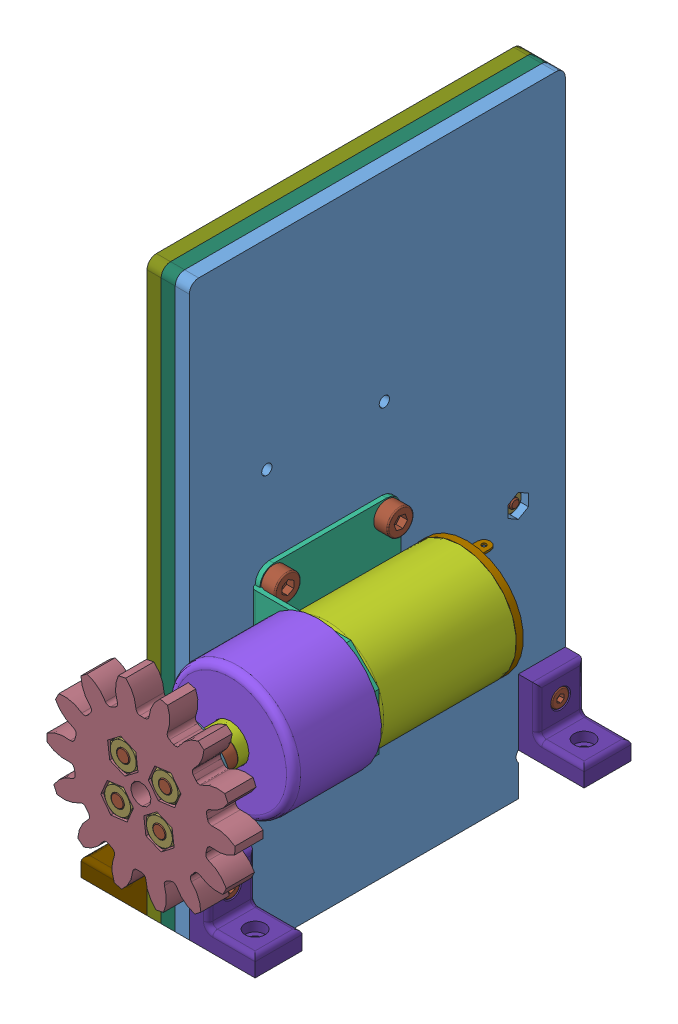
SolidWorks assembly moteur-complet, configuration Défaut. Lengths in mm.
Overall size (65.16 130 104.7).
48 component instances, 19 part files, 74 mates.
Components (placement in the parent):
- moteur-platine-1-4: moteur-platine-1 [Défaut] at (-59.9962 -68.9698 170) size (3 130 80)
- Grove button-1: Grove button [Défaut] at (-66.7015 -12.8903 110) x (0 -1 0) z (0 0 -1) size (20 11.6 23.6)
  - PCB grove 20x20-1: PCB grove 20x20 [Défaut] at (2.0795 1.2947 0) size (20 1.6 23.6)
  - 603 resistor 102-1: 603 resistor 102 [Default] at (2.0895 2.8947 -6.319) x (0 0 1) z (-1 0 0) size (2.36 0.62 1.03)
  - tactileswitch-CMS-1: tactileswitch-CMS [Default] at (-2.4169 2.8947 0.0035) x (0 0 1) z (-1 0 0) size (8.41 4.95 6.01)
  - Connecteur Grove (droit CMS)-1: Connecteur Grove (droit CMS) [Défaut] at (5.0795 2.8947 0) x (-1 0 0) z (0 1 0) size (6.5 14 10)
  - 603 resistor 102-2: 603 resistor 102 [Default] at (3.5895 2.8947 -6.319) x (0 0 1) z (-1 0 0) size (2.36 0.62 1.03)
- moteur MFA-1: moteur MFA [Défaut] at (-44.4916 -13.5198 141.6132) x (0 0 -1) z (0 -1 0) size (69.13 27.9 30)
  - moteur-support-1: moteur-support [Défaut] at (-14.3868 -12.5047 0) size (31 26.4 30)
  - moteur-corps-1: moteur-corps [Défaut] at (14.8132 1.8953 0) x (0 0 1) z (-1 0 0) size (24 24 62.63)
  - moteur-capuchon-1: moteur-capuchon [Défaut] at (-15.3868 1.8953 0) x (0 0 1) z (-1 0 0) size (27 27 18.7)
  - moteur-arriere-1: moteur-arriere [Défaut] at (16.3132 1.8953 0) x (0 0 1) z (-1 0 0) size (24 24 6.5)
- entretoise-grove-6: entretoise-grove [Défaut] at (-67.9962 -14.9698 120) x (0 0.014606 -0.999893) z (1 0 0) size (4 4 2)
- entretoise-grove-7: entretoise-grove [Défaut] at (-67.9962 -14.9698 100) x (0 0.432952 0.901417) z (1 0 0) size (4 4 2)
- vis-chc-1: vis-chc [Vis CHC M2x12] at (-69.5962 -14.9698 100) x (0 0.697993 -0.716105) z (0 0.716105 0.697993) size (3.8 14 3.8)
- vis-chc-2: vis-chc [Vis CHC M2x12] at (-69.5962 -14.9698 120) x (0 0.185382 -0.982666) z (0 0.982666 0.185382) size (3.8 14 3.8)
- ecrou-h-2: ecrou-h [6007 HU M2] at (-59.9962 -14.9698 120) x (0 0.866025 0.5) z (0 -0.5 0.866025) size (4 1.6 4.62)
- ecrou-h-3: ecrou-h [6007 HU M2] at (-59.9962 -14.9698 100) x (0 0 1) z (0 -1 0) size (4 1.6 4.62)
- vis-chc-8: vis-chc [Vis CHC M3x10] at (-55.9962 -1.5198 129) x (0 0.773717 -0.633531) z (0 -0.633531 -0.773717) size (5.5 13 5.5)
- vis-chc-9: vis-chc [Vis CHC M3x10] at (-55.9962 -1.5198 153) x (0 0.483049 -0.875594) z (0 -0.875594 -0.483049) size (5.5 13 5.5)
- vis-chc-10: vis-chc [Vis CHC M3x10] at (-55.9962 -25.5198 153) x (0 0.381849 -0.924225) z (0 -0.924225 -0.381849) size (5.5 13 5.5)
- vis-chc-11: vis-chc [Vis CHC M3x10] at (-55.9962 -25.5198 129) x (0 0.381849 -0.924225) z (0 -0.924225 -0.381849) size (5.5 13 5.5)
- ecrou-h-9: ecrou-h [6012 HU M3] at (-65.3962 -1.5198 153) x (0 0.866025 0.5) z (0 -0.5 0.866025) size (5.5 2.4 6.35)
- ecrou-h-10: ecrou-h [6012 HU M3] at (-65.3962 -25.5198 153) x (0 0.866025 0.5) z (0 -0.5 0.866025) size (5.5 2.4 6.35)
- ecrou-h-11: ecrou-h [6012 HU M3] at (-65.3962 -25.5198 129) x (0 0.866025 -0.5) z (0 0.5 0.866025) size (5.5 2.4 6.35)
- ecrou-h-12: ecrou-h [6012 HU M3] at (-65.3962 -1.5198 129) x (0 0.866025 -0.5) z (0 0.5 0.866025) size (5.5 2.4 6.35)
- vis-chc-14: vis-chc [Vis CHC M2x16] at (-54.9962 -50.9698 95) x (0 -0.431797 -0.901971) z (0 -0.901971 0.431797) size (3.8 18 3.8)
- vis-chc-15: vis-chc [Vis CHC M2x16] at (-54.9962 -50.9698 165) x (0 0.381849 -0.924225) z (0 -0.924225 -0.381849) size (3.8 18 3.8)
- ecrou-h-15: ecrou-h [6007 HU M2] at (-69.5962 -50.9698 165) x (0 1 0) z (0 0 1) size (4 1.6 4.62)
- ecrou-h-16: ecrou-h [6007 HU M2] at (-69.5962 -50.9698 95) x (0 0.5 0.866025) z (0 -0.866025 0.5) size (4 1.6 4.62)
- engrenage-complet-1: engrenage-complet [Défaut] at (-43.0713 -13.4207 194.7) x (-0.795458 -0.606009 0) z (0 0 -1) size (39.32 40 13)
  - engrenage-1: engrenage [Défaut] at (1.0609 0.1936 0) size (39.32 40 6)
  - vis-chc-2: vis-chc [Vis CHC M3x10] at (6.0322 -0.3667 10) x (0.997256 0.074024 0) z (0.074024 -0.997256 0) size (5.5 13 5.5)
  - ecrou-h-1: ecrou-h [6012 HU M3] at (6.0322 -0.3667 0.1) x (1 0 0) z (0 1 0) size (5.5 2.4 6.35)
  - engrenage-moyeu-1: engrenage-moyeu [Défaut] at (-0.3178 -0.3667 7.5) x (0.707107 -0.707107 0) z (0 0 1) size (19 19 5)
  - vis-chc-3: vis-chc [Vis CHC M3x10] at (-0.3178 5.9833 10) x (0.997256 0.074024 0) z (0.074024 -0.997256 0) size (5.5 13 5.5)
  - vis-chc-4: vis-chc [Vis CHC M3x10] at (-6.6678 -0.3667 10) x (0.997256 0.074024 0) z (0.074024 -0.997256 0) size (5.5 13 5.5)
  - vis-chc-5: vis-chc [Vis CHC M3x10] at (-0.3178 -6.7167 10) x (0.997256 0.074024 0) z (0.074024 -0.997256 0) size (5.5 13 5.5)
  - ecrou-h-2: ecrou-h [6012 HU M3] at (-6.6678 -0.3667 0.1) x (0.5 0.866025 0) z (-0.866025 0.5 0) size (5.5 2.4 6.35)
  - ecrou-h-3: ecrou-h [6012 HU M3] at (-0.3178 5.9833 0.1) x (0.866025 0.5 0) z (-0.5 0.866025 0) size (5.5 2.4 6.35)
  - ecrou-h-4: ecrou-h [6012 HU M3] at (-0.3178 -6.7167 0.1) x (0.866025 0.5 0) z (-0.5 0.866025 0) size (5.5 2.4 6.35)
- moteur-platine-2-5: moteur-platine-2 [Défaut] at (-62.9962 -68.9698 170) size (3 130 80)
- moteur-platine-3-3: moteur-platine-3 [Défaut] at (-65.9962 -68.9698 170) size (3 130 80)
- equerre-3: equerre [Défaut] at (-56.9962 -59.9698 165) x (0 0 -1) z (1 0 0) size (10 14 14)
- equerre-2: equerre [Défaut] at (-56.9962 -59.9698 95) x (0 0 -1) z (1 0 0) size (10 14 14)
- equerre-ecrou-1: equerre-ecrou [Défaut] at (-65.9962 -59.9698 95) x (0 0 1) z (-1 0 0) size (10 14 14)
- equerre-ecrou-2: equerre-ecrou [Défaut] at (-65.9962 -59.9698 165) x (0 0 1) z (-1 0 0) size (10 14 14)
- vis-sthc-m3x5-1: vis-sthc-m3x5 [Défaut] at (-41.6585 -6.5829 187.2) x (-0.051839 0.007008 0.998631) z (0.133961 0.990987 0) size (3.08 3.15 5.22)
Mates (geometry in assembly coordinates):
- Coïncidente1: coincident anti-aligned: plane of moteur-platine-1-4 through (-56.9962 -61.1012 161.1314) normal (1 0 0); plane of moteur MFA-1/moteur-support-1 through (-56.9962 -25.5198 153) normal (-1 0 0)
- Coaxiale1: concentric anti-aligned: cylinder of moteur-platine-1-4 through (-59.9962 -1.5198 129) axis (1 0 0) radius 1.6; cylinder of moteur MFA-1/moteur-support-1 through (-30.5962 -1.5198 129) axis (-1 0 0) radius 1.65
- Coaxiale2: concentric anti-aligned: cylinder of moteur-platine-1-4 through (-59.9962 -25.5198 129) axis (1 0 0) radius 1.6; cylinder of moteur MFA-1/moteur-support-1 through (-30.5962 -25.5198 129) axis (-1 0 0) radius 1.65
- Coaxiale9: concentric anti-aligned: cylinder of Grove button-1/PCB grove 20x20-1 through (-69.5962 -14.9698 120) axis (1 0 0) radius 1.1; cylinder of entretoise-grove-6 through (-65.9962 -14.9698 120) axis (-1 0 0) radius 1.2
- Coaxiale10: concentric anti-aligned: cylinder of Grove button-1/PCB grove 20x20-1 through (-69.5962 -14.9698 100) axis (1 0 0) radius 1.1; cylinder of entretoise-grove-7 through (-65.9962 -14.9698 100) axis (-1 0 0) radius 1.2
- Coïncidente11: coincident anti-aligned: plane of Grove button-1/PCB grove 20x20-1 through (-67.9962 -14.9698 110) normal (1 0 0); plane of entretoise-grove-7 through (-67.9962 -14.9698 100) normal (-1 0 0)
- Coaxiale13: concentric anti-aligned: cylinder of moteur MFA-1/moteur-corps-1 through (-42.5962 -13.5198 189.43) axis (0 0 -1) radius 2; cylinder of engrenage-complet-1/engrenage-bague_arret-1 through (-42.5962 -13.5198 179.93) axis (0 0 1) radius 2.05
- Distance1: distance = 0.5 mm anti-aligned: plane of engrenage-complet-1/engrenage-bague_arret-1 through (-42.5962 -13.5198 179.93) normal (0 0 -1); plane of moteur MFA-1/moteur-corps-1 through (-42.5962 -13.5198 179.43) normal (0 0 1)
- Coïncidente12: coincident anti-aligned: plane of moteur-platine-1-4 through (-59.9962 -61.1012 161.1314) normal (-1 0 0); plane of moteur-platine-2-5 through (-59.9962 -61.1012 161.1314) normal (1 0 0)
- Coïncidente13: coincident aligned: plane of moteur-platine-1-4 through (-56.9962 61.0302 170) normal (0 1 0); plane of moteur-platine-2-5 through (-59.9962 61.0302 170) normal (0 1 0)
- Coïncidente14: coincident aligned: plane of moteur-platine-1-4 through (-56.9962 61.0302 90) normal (0 0 -1); plane of moteur-platine-2-5 through (-59.9962 61.0302 90) normal (0 0 -1)
- Coïncidente15: coincident anti-aligned: plane of moteur-platine-2-5 through (-62.9962 -61.1012 161.1314) normal (-1 0 0); plane of moteur-platine-3-3 through (-62.9962 -61.1012 161.1314) normal (1 0 0)
- Coïncidente16: coincident aligned: plane of moteur-platine-2-5 through (-59.9962 61.0302 170) normal (0 1 0); plane of moteur-platine-3-3 through (-62.9962 61.0302 170) normal (0 1 0)
- Coïncidente17: coincident aligned: plane of moteur-platine-1-4 through (-56.9962 61.0302 90) normal (0 0 -1); plane of moteur-platine-3-3 through (-62.9962 61.0302 90) normal (0 0 -1)
- Coïncidente18: coincident anti-aligned: plane of entretoise-grove-7 through (-65.9962 -14.9698 100) normal (1 0 0); plane of moteur-platine-3-3 through (-65.9962 -61.1012 161.1314) normal (-1 0 0)
- Coïncidente19: coincident anti-aligned: plane of entretoise-grove-6 through (-65.9962 -14.9698 120) normal (1 0 0); plane of moteur-platine-3-3 through (-65.9962 -61.1012 161.1314) normal (-1 0 0)
- Coïncidente21: coincident anti-aligned: plane of Grove button-1/PCB grove 20x20-1 through (-69.5962 -14.9698 110) normal (-1 0 0); plane of vis-chc-2 through (-69.5962 -14.9698 120) normal (1 0 0)
- Coaxiale15: concentric aligned: cylinder of vis-chc-2 through (-57.5962 -14.9698 120) axis (-1 0 0) radius 1; cylinder of ecrou-h-2 through (-58.3962 -14.9698 120) axis (-1 0 0) radius 0.7835
- Parallèle4: parallel aligned: plane of moteur-platine-1-4 through (-56.9962 61.0302 90) normal (0 0 -1); plane of ecrou-h-2 through (-58.3962 -13.8151 118) normal (0 0 -1)
- Coïncidente25: coincident anti-aligned: plane of Grove button-1/PCB grove 20x20-1 through (-69.5962 -14.9698 110) normal (-1 0 0); plane of vis-chc-1 through (-69.5962 -14.9698 100) normal (1 0 0)
- Coaxiale17: concentric aligned: cylinder of vis-chc-1 through (-57.5962 -14.9698 100) axis (-1 0 0) radius 1; cylinder of ecrou-h-3 through (-58.3962 -14.9698 100) axis (-1 0 0) radius 0.7835
- Parallèle5: parallel aligned: plane of moteur-platine-1-4 through (-56.9962 61.0302 90) normal (0 0 -1); plane of ecrou-h-3 through (-58.3962 -13.8151 98) normal (0 0 -1)
- Coaxiale28: concentric anti-aligned: cylinder of moteur MFA-1/moteur-support-1 through (-30.5962 -1.5198 153) axis (-1 0 0) radius 1.65; cylinder of vis-chc-9 through (-65.9962 -1.5198 153) axis (1 0 0) radius 1.5
- Coaxiale29: concentric anti-aligned: cylinder of moteur MFA-1/moteur-support-1 through (-30.5962 -1.5198 129) axis (-1 0 0) radius 1.65; cylinder of vis-chc-8 through (-65.9962 -1.5198 129) axis (1 0 0) radius 1.5
- Coaxiale30: concentric anti-aligned: cylinder of moteur MFA-1/moteur-support-1 through (-30.5962 -25.5198 129) axis (-1 0 0) radius 1.65; cylinder of vis-chc-11 through (-65.9962 -25.5198 129) axis (1 0 0) radius 1.5
- Coaxiale31: concentric anti-aligned: cylinder of moteur MFA-1/moteur-support-1 through (-30.5962 -25.5198 153) axis (-1 0 0) radius 1.65; cylinder of vis-chc-10 through (-65.9962 -25.5198 153) axis (1 0 0) radius 1.5
- Coïncidente43: coincident anti-aligned: plane of moteur MFA-1/moteur-support-1 through (-55.9962 -29.752 156) normal (1 0 0); plane of vis-chc-11 through (-55.9962 -25.5198 129) normal (-1 0 0)
- Coïncidente44: coincident aligned: plane of moteur MFA-1/moteur-support-1 through (-55.9962 -29.752 156) normal (1 0 0); circle of vis-chc-10
- Coïncidente45: coincident anti-aligned: plane of moteur MFA-1/moteur-support-1 through (-55.9962 -29.752 156) normal (1 0 0); plane of vis-chc-8 through (-55.9962 -1.5198 129) normal (-1 0 0)
- Coïncidente46: coincident anti-aligned: plane of moteur MFA-1/moteur-support-1 through (-55.9962 -29.752 156) normal (1 0 0); plane of vis-chc-9 through (-55.9962 -1.5198 153) normal (-1 0 0)
- Coaxiale32: concentric anti-aligned: cylinder of vis-chc-8 through (-65.9962 -1.5198 129) axis (1 0 0) radius 1.5; cylinder of ecrou-h-12 through (-62.9962 -1.5198 129) axis (-1 0 0) radius 1.2295
- Coaxiale33: concentric anti-aligned: cylinder of vis-chc-10 through (-65.9962 -25.5198 153) axis (1 0 0) radius 1.5; cylinder of ecrou-h-10 through (-62.9962 -25.5198 153) axis (-1 0 0) radius 1.2295
- Coaxiale34: concentric anti-aligned: cylinder of vis-chc-9 through (-65.9962 -1.5198 153) axis (1 0 0) radius 1.5; cylinder of ecrou-h-9 through (-62.9962 -1.5198 153) axis (-1 0 0) radius 1.2295
- Coaxiale35: concentric anti-aligned: cylinder of vis-chc-11 through (-65.9962 -25.5198 129) axis (1 0 0) radius 1.5; cylinder of ecrou-h-11 through (-62.9962 -25.5198 129) axis (-1 0 0) radius 1.2295
- Parallèle11: parallel aligned: plane of moteur-platine-3-3 through (-62.9962 -59.9698 170) normal (0 0 1); plane of ecrou-h-10 through (-62.9962 -27.1075 155.75) normal (0 0 1)
- Parallèle12: parallel aligned: plane of moteur-platine-3-3 through (-62.9962 -59.9698 170) normal (0 0 1); plane of ecrou-h-11 through (-62.9962 -27.1075 131.75) normal (0 0 1)
- Parallèle13: parallel aligned: plane of moteur-platine-3-3 through (-62.9962 -59.9698 170) normal (0 0 1); plane of ecrou-h-12 through (-62.9962 -3.1075 131.75) normal (0 0 1)
- Parallèle14: parallel aligned: plane of moteur-platine-3-3 through (-62.9962 -59.9698 170) normal (0 0 1); plane of ecrou-h-9 through (-62.9962 -3.1075 155.75) normal (0 0 1)
- Coïncidente62: coincident anti-aligned: plane of moteur-platine-1-4 through (-56.9962 -61.1012 161.1314) normal (1 0 0); plane of equerre-2 through (-56.9962 -59.9698 95) normal (-1 0 0)
- Coaxiale41: concentric aligned: cylinder of moteur-platine-1-4 through (-59.9962 -50.9698 95) axis (1 0 0) radius 1.1; cylinder of equerre-2 through (-56.9962 -50.9698 95) axis (1 0 0) radius 1.1
- Coïncidente63: coincident aligned: plane of moteur-platine-1-4 through (-56.9962 -59.9698 97.7373) normal (0 -1 0); plane of equerre-2 through (-52.9962 -59.9698 100) normal (0 -1 0)
- Coaxiale42: concentric aligned: cylinder of moteur-platine-1-4 through (-59.9962 -50.9698 165) axis (1 0 0) radius 1.1; cylinder of equerre-3 through (-56.9962 -50.9698 165) axis (1 0 0) radius 1.1
- Coïncidente64: coincident aligned: plane of moteur-platine-1-4 through (-56.9962 -59.9698 162.2627) normal (0 -1 0); plane of equerre-3 through (-52.9962 -59.9698 170) normal (0 -1 0)
- Coïncidente65: coincident anti-aligned: plane of moteur-platine-1-4 through (-56.9962 -61.1012 161.1314) normal (1 0 0); plane of equerre-3 through (-56.9962 -59.9698 165) normal (-1 0 0)
- Coaxiale43: concentric aligned: cylinder of vis-chc-15 through (-70.9962 -50.9698 165) axis (1 0 0) radius 1; cylinder of equerre-3 through (-56.9962 -50.9698 165) axis (1 0 0) radius 1.1
- Coïncidente66: coincident anti-aligned: plane of vis-chc-15 through (-54.9962 -50.9698 165) normal (-1 0 0); plane of equerre-3 through (-54.9962 -50.9698 165) normal (1 0 0)
- Coaxiale44: concentric aligned: cylinder of vis-chc-14 through (-70.9962 -50.9698 95) axis (1 0 0) radius 1; cylinder of equerre-2 through (-56.9962 -50.9698 95) axis (1 0 0) radius 1.1
- Coïncidente67: coincident anti-aligned: plane of vis-chc-14 through (-54.9962 -50.9698 95) normal (-1 0 0); plane of equerre-2 through (-54.9962 -50.9698 95) normal (1 0 0)
- Coïncidente68: coincident anti-aligned: plane of moteur-platine-3-3 through (-65.9962 -61.1012 161.1314) normal (-1 0 0); plane of equerre-ecrou-2 through (-65.9962 -59.9698 165) normal (1 0 0)
- Coïncidente69: coincident anti-aligned: plane of moteur-platine-3-3 through (-65.9962 -61.1012 161.1314) normal (-1 0 0); plane of equerre-ecrou-1 through (-65.9962 -59.9698 95) normal (1 0 0)
- Coïncidente70: coincident aligned: plane of moteur-platine-3-3 through (-62.9962 -59.9698 97.7373) normal (0 -1 0); plane of equerre-ecrou-1 through (-69.9962 -59.9698 90) normal (0 -1 0)
- Coïncidente71: coincident aligned: plane of moteur-platine-3-3 through (-62.9962 -59.9698 97.7373) normal (0 -1 0); plane of equerre-ecrou-2 through (-69.9962 -59.9698 160) normal (0 -1 0)
- Coaxiale45: concentric anti-aligned: cylinder of vis-chc-14 through (-70.9962 -50.9698 95) axis (1 0 0) radius 1; cylinder of equerre-ecrou-1 through (-65.9962 -50.9698 95) axis (-1 0 0) radius 1.1
- Coaxiale46: concentric anti-aligned: cylinder of vis-chc-15 through (-70.9962 -50.9698 165) axis (1 0 0) radius 1; cylinder of equerre-ecrou-2 through (-65.9962 -50.9698 165) axis (-1 0 0) radius 1.1
- Coaxiale47: concentric anti-aligned: cylinder of vis-chc-15 through (-70.9962 -50.9698 165) axis (1 0 0) radius 1; cylinder of ecrou-h-15 through (-67.9962 -50.9698 165) axis (-1 0 0) radius 0.7835
- Parallèle18: parallel anti-aligned: plane of ecrou-h-15 through (-67.9962 -48.9698 166.1547) normal (0 1 0); plane of equerre-ecrou-2 through (-67.9962 -48.8047 166.25) normal (0 -1 0)
- Coïncidente73: coincident anti-aligned: plane of ecrou-h-15 through (-67.9962 -48.9698 163.8453) normal (1 0 0); plane of equerre-ecrou-2 through (-67.9962 -59.9698 165) normal (-1 0 0)
- Coaxiale49: concentric anti-aligned: cylinder of vis-chc-14 through (-70.9962 -50.9698 95) axis (1 0 0) radius 1; cylinder of ecrou-h-16 through (-67.9962 -50.9698 95) axis (-1 0 0) radius 0.7835
- Parallèle19: parallel anti-aligned: plane of ecrou-h-16 through (-67.9962 -48.9698 96.1547) normal (0 1 0); plane of equerre-ecrou-1 through (-67.9962 -48.8047 96.25) normal (0 -1 0)
- Coïncidente75: coincident anti-aligned: plane of ecrou-h-16 through (-67.9962 -48.9698 96.1547) normal (1 0 0); plane of equerre-ecrou-1 through (-67.9962 -59.9698 95) normal (-1 0 0)
- Coïncidente81: coincident anti-aligned: plane of ecrou-h-12 through (-62.9962 0.0679 126.25) normal (1 0 0); plane of moteur-platine-2-5 through (-62.9962 -61.1012 161.1314) normal (-1 0 0)
- Coïncidente82: coincident anti-aligned: plane of ecrou-h-11 through (-62.9962 -23.9321 126.25) normal (1 0 0); plane of moteur-platine-2-5 through (-62.9962 -61.1012 161.1314) normal (-1 0 0)
- Coïncidente83: coincident anti-aligned: plane of ecrou-h-10 through (-62.9962 -22.3444 153) normal (1 0 0); plane of moteur-platine-2-5 through (-62.9962 -61.1012 161.1314) normal (-1 0 0)
- Coïncidente84: coincident anti-aligned: plane of ecrou-h-9 through (-62.9962 1.6556 153) normal (1 0 0); plane of moteur-platine-2-5 through (-62.9962 -61.1012 161.1314) normal (-1 0 0)
- Coaxiale50: concentric anti-aligned: cylinder of vis-chc-2 through (-57.5962 -14.9698 120) axis (-1 0 0) radius 1; cylinder of moteur-platine-3-3 through (-65.9962 -14.9698 120) axis (1 0 0) radius 1
- Coaxiale51: concentric anti-aligned: cylinder of vis-chc-1 through (-57.5962 -14.9698 100) axis (-1 0 0) radius 1; cylinder of moteur-platine-3-3 through (-65.9962 -14.9698 100) axis (1 0 0) radius 1
- Coïncidente85: coincident anti-aligned: plane of ecrou-h-3 through (-59.9962 -13.8151 102) normal (-1 0 0); plane of moteur-platine-2-5 through (-59.9962 -61.1012 161.1314) normal (1 0 0)
- Coïncidente86: coincident anti-aligned: plane of ecrou-h-2 through (-59.9962 -12.6604 120) normal (-1 0 0); plane of moteur-platine-2-5 through (-59.9962 -61.1012 161.1314) normal (1 0 0)
- Coaxiale52: concentric anti-aligned: cylinder of Grove button-1/PCB grove 20x20-1 through (-69.5962 -14.9698 100) axis (1 0 0) radius 1.1; cylinder of vis-chc-1 through (-57.5962 -14.9698 100) axis (-1 0 0) radius 1
- Coaxiale53: concentric anti-aligned: cylinder of Grove button-1/PCB grove 20x20-1 through (-69.5962 -14.9698 120) axis (1 0 0) radius 1.1; cylinder of vis-chc-2 through (-57.5962 -14.9698 120) axis (-1 0 0) radius 1
- Coaxiale54: concentric aligned: cylinder of engrenage-complet-1/engrenage-moyeu-1 through (-40.4528 2.336 187.2) axis (-0.133961 -0.990987 0) radius 1.5; cone of vis-sthc-m3x5-1 through (-42.2948 -11.2901 187.2) axis (-0.133961 -0.990987 0)
- Coaxiale55: concentric anti-aligned: cylinder of moteur MFA-1/moteur-corps-1 through (-42.5962 -13.5198 189.43) axis (0 0 -1) radius 2; cylinder of engrenage-complet-1/engrenage-moyeu-1 through (-42.5962 -13.5198 184.7) axis (0 0 1) radius 2
- Tangent1: tangent anti-aligned: cylinder of moteur MFA-1/moteur-corps-1 through (-42.5962 -13.5198 189.43) axis (0 0 -1) radius 2; plane of vis-sthc-m3x5-1 through (-42.3283 -11.5378 187.2) normal (-0.133961 -0.990987 0)
- Distance2: distance = 13 mm anti-aligned: plane of engrenage-complet-1/engrenage-1 through (-42.5962 -13.5198 188.7) normal (0 0 -1); plane of moteur MFA-1/moteur-capuchon-1 through (-42.5962 -13.5198 175.7) normal (0 0 1)
